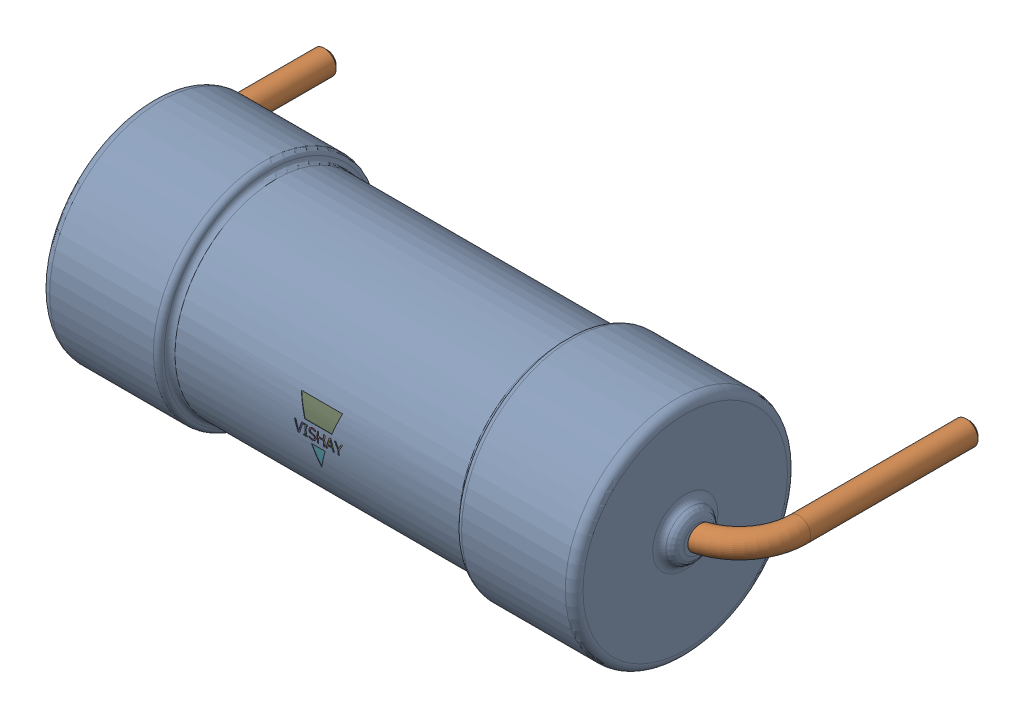
SolidWorks assembly Res_Vishay_AC05000003909JAC00_eec.step, configuration Default. Lengths in mm.
Overall size (22.46 7.5 11.5).
3 component instances, 3 part files, 0 mates.
Components (placement in the parent):
- AC0500000XXXJAC00.step-1: AC0500000XXXJAC00.step [Default] at (-37 0 3.75) size (18.87 7.5 7.5)
- 1-4.step-1: 1-4.step [Default] at (0 0 -8) x (1 0 0) z (0 -1 0) size (22.46 8.15 0.8)
- 2-5.step-1: 2-5.step [Default] at (-37 0 3.75) size (1.63 1.9 3.41)
